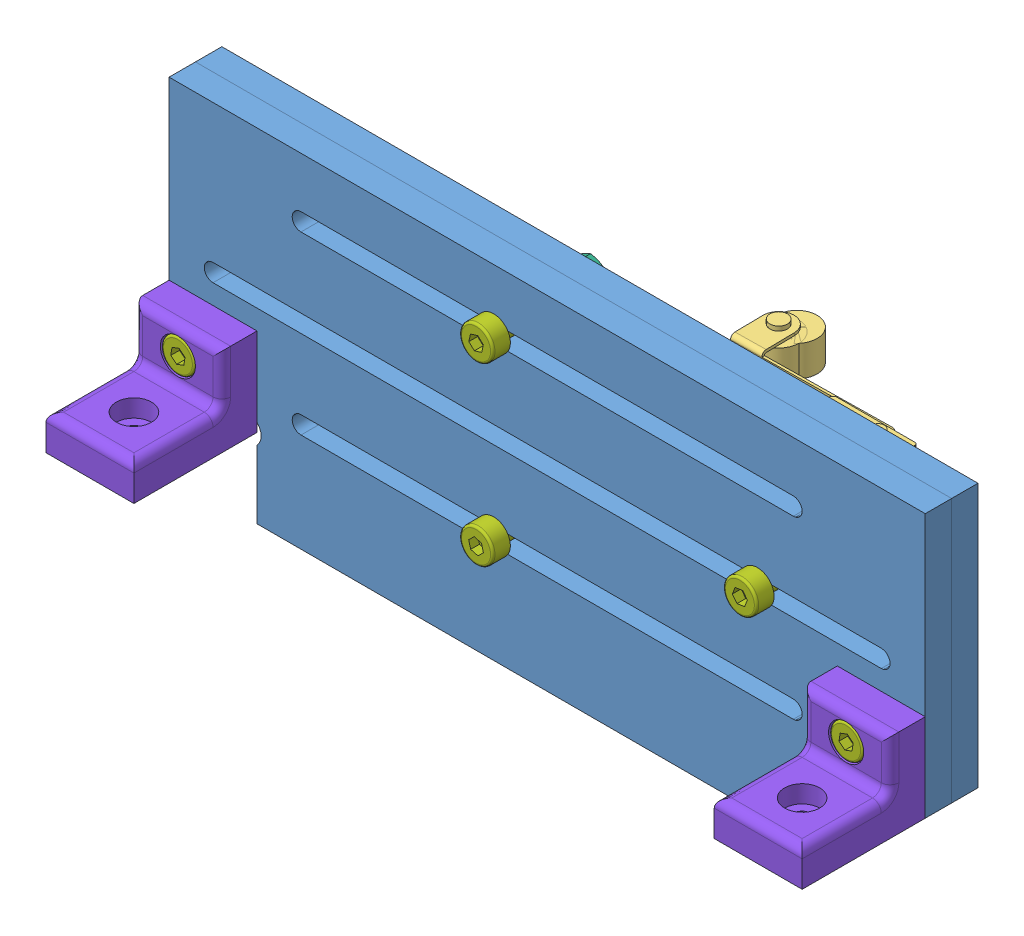
SolidWorks assembly cfc_ferme, configuration Défaut. Lengths in mm.
Overall size (86 39 42.4).
21 component instances, 8 part files, 46 mates.
Components (placement in the parent):
- cfc-platine-1: cfc-platine [Défaut] at (140.8628 -70 0) x (0 0 1) z (0 -1 0) size (3 86 39)
- Grove microswitch v1.0-1: Grove microswitch v1.0 [Défaut] at (-37.098 22.25 -3.344) x (1 0 0) z (0 1 0) size (41.8 22.4 23.6)
  - PCB grove 20x40-1: PCB grove 20x40 [Défaut] at (-1.988 -1.344 0) size (41.8 1.6 23.6)
  - microswitch 10T85-1: microswitch 10T85 [Défaut] at (9.562 0.256 0) size (22.48 22.4 6.4)
  - Connecteur Grove (coudé CMS)-1: Connecteur Grove (coudé CMS) [Défaut] at (-21.488 0.256 0) x (0 0 -1) z (0 1 0) size (12 10 5)
- entretoise-grove-1: entretoise-grove [Défaut] at (-19.086 22.25 -2) x (1 0.000242 0) z (0 0 1) size (4 4 2)
- entretoise-grove-2: entretoise-grove [Défaut] at (-49.086 12.25 -2) size (4 4 2)
- entretoise-grove-3: entretoise-grove [Défaut] at (-49.086 32.25 -2) size (4 4 2)
- ecrou-h-1: ecrou-h [6007 HU M2] at (-19.086 22.25 -3.6) x (0.5 0.866025 0) z (0.866025 -0.5 0) size (4 1.6 4.62)
- ecrou-h-2: ecrou-h [6007 HU M2] at (-49.086 12.25 -3.6) x (1 0 0) z (0 -1 0) size (4 1.6 4.62)
- ecrou-h-3: ecrou-h [6007 HU M2] at (-49.086 32.25 -3.6) x (-0.5 0.866025 0) z (0.866025 0.5 0) size (4 1.6 4.62)
- vis-chc-1: vis-chc [Vis CHC M2x12] at (-49.086 12.25 6) x (0.689734 0.724063 0) z (0.724063 -0.689734 0) size (3.8 14 3.8)
- vis-chc-2: vis-chc [Vis CHC M2x12] at (-49.086 32.25 6) x (-0.193562 -0.981088 0) z (-0.981088 0.193562 0) size (3.8 14 3.8)
- vis-chc-3: vis-chc [Vis CHC M2x12] at (-19.086 22.25 6) x (-0.643508 0.765439 0) z (0.765439 0.643508 0) size (3.8 14 3.8)
- ecrou-h-5: ecrou-h [6007 HU M2] at (-81 16 -1.6) x (1 0 0) z (0 1 0) size (4 1.6 4.62)
- ecrou-h-6: ecrou-h [6007 HU M2] at (-5 16 -1.6) x (1 0 0) z (0 1 0) size (4 1.6 4.62)
- vis-chc-6: vis-chc [Vis CHC M2x10] at (-5 16 8) x (-0.923728 -0.383049 0) z (-0.383049 0.923728 0) size (3.8 12 3.8)
- vis-chc-7: vis-chc [Vis CHC M2x10] at (-81 16 8) x (-0.923728 -0.383049 0) z (-0.383049 0.923728 0) size (3.8 12 3.8)
- cfc-platine-2: cfc-platine [Défaut] at (140.8628 -70 3) x (0 0 1) z (0 -1 0) size (3 86 39)
- equerre-basse-1: equerre-basse [Défaut] at (-81 9 6) size (10 10 14)
- equerre-basse-2: equerre-basse [Défaut] at (-5 9 6) size (10 10 14)
Mates (geometry in assembly coordinates):
- Coïncidente1: coincident anti-aligned: plane of cfc-platine-1 through (-8.8686 8.8686 0) normal (0 0 -1)
- Coïncidente2: coincident anti-aligned: plane of cfc-platine-1 through (-10 0 3) normal (0 -1 0)
- Coaxiale1: concentric anti-aligned: cylinder of Grove microswitch v1.0-1/PCB grove 20x40-1 through (-49.086 32.25 -3.6) axis (0 0 1) radius 1.1; cylinder of entretoise-grove-3 through (-49.086 32.25 0) axis (0 0 -1) radius 1.1
- Coïncidente4: coincident anti-aligned: plane of Grove microswitch v1.0-1/PCB grove 20x40-1 through (-39.086 22.25 -2) normal (0 0 1); plane of entretoise-grove-3 through (-49.086 32.25 -2) normal (0 0 -1)
- Coaxiale2: concentric anti-aligned: cylinder of Grove microswitch v1.0-1/PCB grove 20x40-1 through (-19.086 22.25 -3.6) axis (0 0 1) radius 1.1; cylinder of entretoise-grove-1 through (-19.086 22.25 0) axis (0 0 -1) radius 1.1
- Coïncidente5: coincident anti-aligned: plane of Grove microswitch v1.0-1/PCB grove 20x40-1 through (-39.086 22.25 -2) normal (0 0 1); plane of entretoise-grove-1 through (-19.086 22.25 -2) normal (0 0 -1)
- Coaxiale3: concentric anti-aligned: cylinder of Grove microswitch v1.0-1/PCB grove 20x40-1 through (-49.086 12.25 -3.6) axis (0 0 1) radius 1.1; cylinder of entretoise-grove-2 through (-49.086 12.25 0) axis (0 0 -1) radius 1.1
- Coïncidente6: coincident anti-aligned: plane of Grove microswitch v1.0-1/PCB grove 20x40-1 through (-39.086 22.25 -2) normal (0 0 1); plane of entretoise-grove-2 through (-49.086 12.25 -2) normal (0 0 -1)
- Coïncidente7: coincident anti-aligned: plane of cfc-platine-1 through (-8.8686 8.8686 0) normal (0 0 -1); plane of entretoise-grove-1 through (-19.086 22.25 0) normal (0 0 1)
- Parallèle4: parallel anti-aligned: plane of cfc-platine-1 through (-86 39 3) normal (-1 0 0); plane of Grove microswitch v1.0-1/PCB grove 20x40-1 through (-19.086 22.25 -3.6) normal (1 0 0)
- Parallèle3: parallel anti-aligned: plane of cfc-platine-1 through (-10 0 3) normal (0 -1 0); plane of Grove microswitch v1.0-1/PCB grove 20x40-1 through (-39.086 32.25 -3.6) normal (0 1 0)
- Coaxiale7: concentric aligned: cylinder of ecrou-h-2 through (-49.086 12.25 -5.2) axis (0 0 1) radius 0.7835; cylinder of vis-chc-1 through (-49.086 12.25 -6) axis (0 0 1) radius 1
- Coaxiale8: concentric aligned: cylinder of ecrou-h-3 through (-49.086 32.25 -5.2) axis (0 0 1) radius 0.7835; cylinder of vis-chc-2 through (-49.086 32.25 -6) axis (0 0 1) radius 1
- Coaxiale9: concentric aligned: cylinder of ecrou-h-1 through (-19.086 22.25 -5.2) axis (0 0 1) radius 0.7835; cylinder of vis-chc-3 through (-19.086 22.25 -6) axis (0 0 1) radius 1
- Tangent1: tangent anti-aligned: plane of cfc-platine-1 through (-5 21.25 3) normal (0 1 0); cylinder of vis-chc-3 through (-19.086 22.25 -6) axis (0 0 1) radius 1
- Coïncidente8: coincident anti-aligned: plane of Grove microswitch v1.0-1/PCB grove 20x40-1 through (-39.086 22.25 -3.6) normal (0 0 -1); plane of ecrou-h-1 through (-19.086 24.5594 -3.6) normal (0 0 1)
- Parallèle10: parallel anti-aligned: plane of Grove microswitch v1.0-1/microswitch 10T85-1 through (-21.086 25.25 -13.9) normal (1 0 0); plane of ecrou-h-1 through (-21.086 23.4047 -5.2) normal (-1 0 0)
- Coïncidente11: coincident anti-aligned: plane of Grove microswitch v1.0-1/PCB grove 20x40-1 through (-39.086 22.25 -3.6) normal (0 0 -1); plane of ecrou-h-2 through (-47.086 13.4047 -3.6) normal (0 0 1)
- Parallèle11: parallel anti-aligned: plane of cfc-platine-1 through (-86 39 3) normal (-1 0 0); plane of ecrou-h-2 through (-47.086 11.0953 -5.2) normal (1 0 0)
- Coïncidente13: coincident anti-aligned: plane of Grove microswitch v1.0-1/PCB grove 20x40-1 through (-39.086 22.25 -3.6) normal (0 0 -1); plane of ecrou-h-3 through (-51.086 33.4047 -3.6) normal (0 0 1)
- Parallèle12: parallel aligned: plane of cfc-platine-1 through (-86 39 3) normal (-1 0 0); plane of ecrou-h-3 through (-51.086 33.4047 -5.2) normal (-1 0 0)
- Coïncidente15: coincident anti-aligned: plane of cfc-platine-1 through (-8.8686 8.8686 3) normal (0 0 1); plane of cfc-platine-2 through (-8.8686 8.8686 3) normal (0 0 -1)
- Coïncidente16: coincident aligned: plane of cfc-platine-1 through (-10 0 3) normal (0 -1 0); plane of cfc-platine-2 through (-10 0 6) normal (0 -1 0)
- Coïncidente17: coincident aligned: plane of cfc-platine-1 through (-86 39 3) normal (-1 0 0); plane of cfc-platine-2 through (-86 39 6) normal (-1 0 0)
- Coïncidente19: coincident anti-aligned: plane of vis-chc-2 through (-49.086 32.25 6) normal (0 0 -1); plane of cfc-platine-2 through (-8.8686 8.8686 6) normal (0 0 1)
- Coaxiale10: concentric aligned: cylinder of Grove microswitch v1.0-1/PCB grove 20x40-1 through (-49.086 32.25 -3.6) axis (0 0 1) radius 1.1; cylinder of vis-chc-2 through (-49.086 32.25 -6) axis (0 0 1) radius 1
- Coaxiale11: concentric aligned: cylinder of Grove microswitch v1.0-1/PCB grove 20x40-1 through (-19.086 22.25 -3.6) axis (0 0 1) radius 1.1; cylinder of vis-chc-3 through (-19.086 22.25 -6) axis (0 0 1) radius 1
- Coïncidente21: coincident anti-aligned: plane of vis-chc-3 through (-19.086 22.25 6) normal (0 0 -1); plane of cfc-platine-2 through (-8.8686 8.8686 6) normal (0 0 1)
- Coïncidente22: coincident anti-aligned: plane of vis-chc-1 through (-49.086 12.25 6) normal (0 0 -1); plane of cfc-platine-2 through (-8.8686 8.8686 6) normal (0 0 1)
- Coaxiale12: concentric aligned: cylinder of Grove microswitch v1.0-1/PCB grove 20x40-1 through (-49.086 12.25 -3.6) axis (0 0 1) radius 1.1; cylinder of vis-chc-1 through (-49.086 12.25 -6) axis (0 0 1) radius 1
- Coïncidente23: coincident aligned: plane of cfc-platine-2 through (-78.726 9 6) normal (0 -1 0); plane of equerre-1 through (-86 9 10) normal (0 -1 0)
- Coïncidente24: coincident anti-aligned: plane of cfc-platine-2 through (-8.8686 8.8686 6) normal (0 0 1); plane of equerre-1 through (-81 9 6) normal (0 0 -1)
- Coaxiale13: concentric anti-aligned: cylinder of cfc-platine-2 through (-81 16 6) axis (0 0 -1) radius 1; cylinder of equerre-1 through (-81 16 6) axis (0 0 1) radius 1.1
- Coïncidente25: coincident anti-aligned: plane of cfc-platine-2 through (-8.8686 8.8686 6) normal (0 0 1); plane of equerre-2 through (-5 9 6) normal (0 0 -1)
- Coïncidente26: coincident aligned: plane of cfc-platine-2 through (0 9 6) normal (0 -1 0); plane of equerre-2 through (-10 9 10) normal (0 -1 0)
- Coaxiale14: concentric anti-aligned: cylinder of cfc-platine-2 through (-5 16 6) axis (0 0 -1) radius 1; cylinder of equerre-2 through (-5 16 6) axis (0 0 1) radius 1.1
- Coaxiale16: concentric aligned: cylinder of vis-chc-7 through (-81 16 -2) axis (0 0 1) radius 1; cylinder of equerre-1 through (-81 16 6) axis (0 0 1) radius 1.1
- Coaxiale17: concentric aligned: cylinder of vis-chc-6 through (-5 16 -2) axis (0 0 1) radius 1; cylinder of equerre-2 through (-5 16 6) axis (0 0 1) radius 1.1
- Coïncidente28: coincident anti-aligned: plane of vis-chc-6 through (-5 16 8) normal (0 0 -1); plane of equerre-2 through (-5 16 8) normal (0 0 1)
- Coïncidente29: coincident anti-aligned: plane of vis-chc-7 through (-81 16 8) normal (0 0 -1); plane of equerre-1 through (-81 16 8) normal (0 0 1)
- Coaxiale20: concentric anti-aligned: cylinder of ecrou-h-5 through (-81 16 0) axis (0 0 -1) radius 0.7835; cylinder of vis-chc-7 through (-81 16 -2) axis (0 0 1) radius 1
- Coïncidente33: coincident anti-aligned: plane of cfc-platine-1 through (-8.8686 8.8686 0) normal (0 0 -1); plane of ecrou-h-5 through (-79 14.8453 0) normal (0 0 1)
- Parallèle14: parallel aligned: plane of cfc-platine-1 through (-86 39 3) normal (-1 0 0); plane of ecrou-h-5 through (-83 14.8453 0) normal (-1 0 0)
- Coaxiale22: concentric anti-aligned: cylinder of ecrou-h-6 through (-5 16 0) axis (0 0 -1) radius 0.7835; cylinder of vis-chc-6 through (-5 16 -2) axis (0 0 1) radius 1
- Coïncidente35: coincident anti-aligned: plane of cfc-platine-1 through (-8.8686 8.8686 0) normal (0 0 -1); plane of ecrou-h-6 through (-3 14.8453 0) normal (0 0 1)
- Parallèle15: parallel aligned: plane of cfc-platine-1 through (0 9 3) normal (1 0 0); plane of ecrou-h-6 through (-3 17.1547 0) normal (1 0 0)
